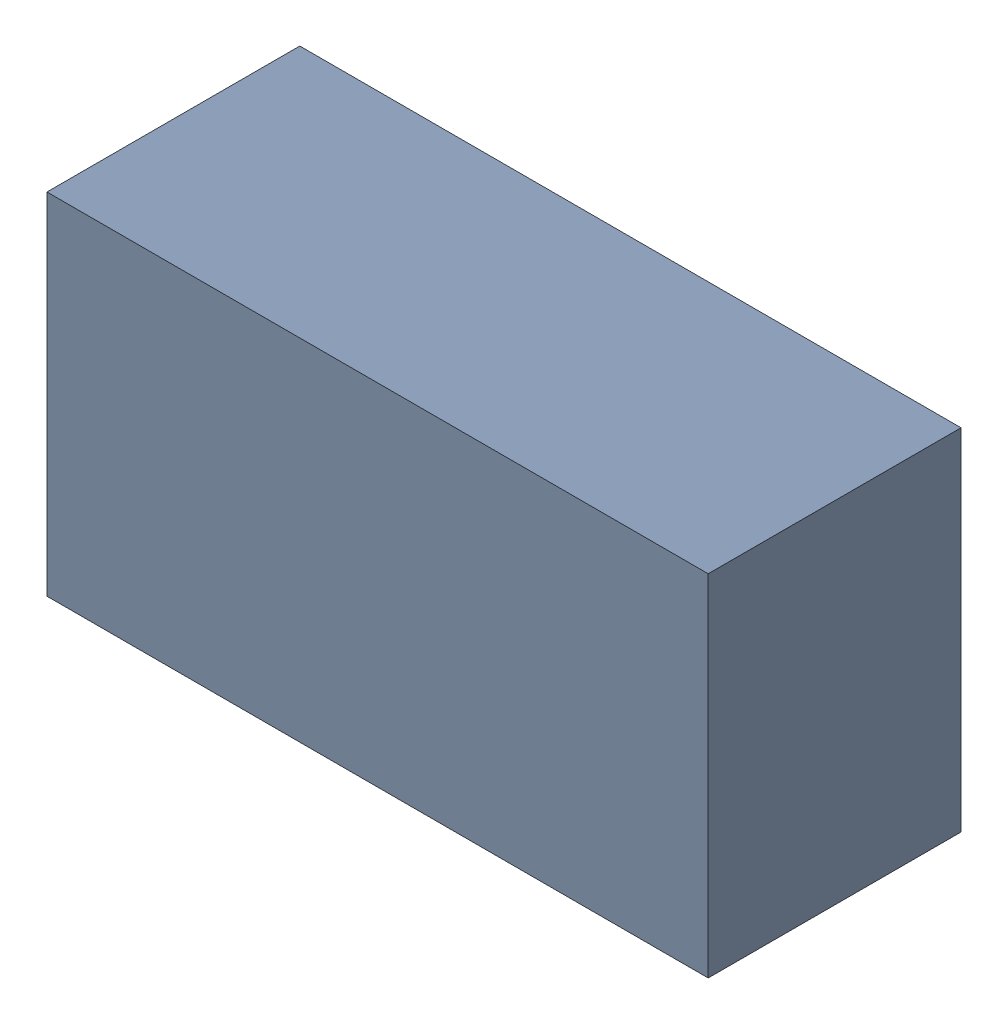
SolidWorks assembly C16, configuration Default. Lengths in mm.
Overall size (3.4 1.8 1.3).
2 component instances, 1 part files, 0 mates.
Components (placement in the parent):
- 1017092976-1: 1017092976 [Default] at (30.48 90.805 0) size (3.4 1.8 1.3)
  - Extruded_4-1: Extruded_4 [Default] at origin size (3.4 1.8 1.3)
